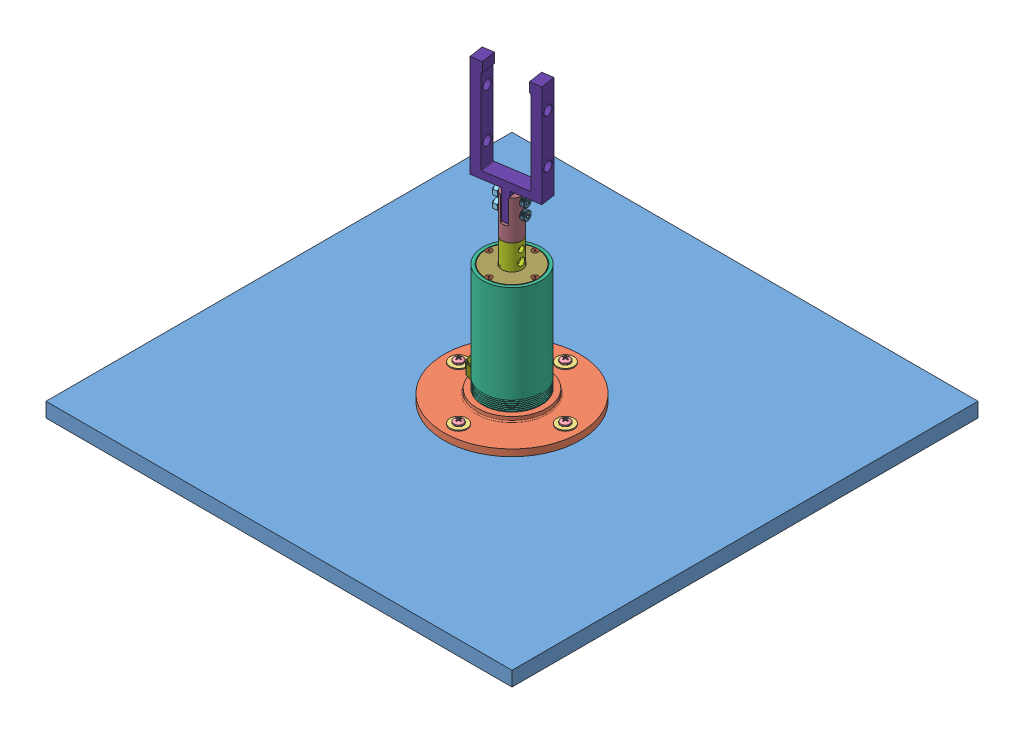
SolidWorks assembly 00_Full Planarizer Assembly, configuration Default. Lengths in mm.
Overall size (609.6 397.76 609.6).
39 component instances, 17 part files, 4 mates.
Components (placement in the parent):
- 00_01_Base_Assembly-1: 00_01_Base_Assembly [Default] at origin size (609.6 258.13 609.6)
  - 00_01_01_Base_Plate-2: 00_01_01_Base_Plate [Default] at (304.8 -19.05 304.8) x (0 0 -1) z (1 0 0) size (609.6 19.05 609.6)
  - 00_01_02_Base_Flange-1: 00_01_02_Base_Flange [Default] at origin size (177.8 15.35 177.8)
  - 00_01_03_91090A107_Zinc-Plated Steel Oversized Washer-2: 00_01_03_91090A107_Zinc-Plated Steel Oversized Washer [91090A107] at (0 10.0584 -69.85) x (0 -1 0) z (0 0 1) size (1.3 22.23 22.23)
  - 00_01_03_91090A107_Zinc-Plated Steel Oversized Washer-1: 00_01_03_91090A107_Zinc-Plated Steel Oversized Washer [91090A107] at (0 10.0584 69.85) x (0 -1 0) z (0 0 -1) size (1.3 22.23 22.23)
  - 00_01_03_91090A107_Zinc-Plated Steel Oversized Washer-3: 00_01_03_91090A107_Zinc-Plated Steel Oversized Washer [91090A107] at (69.85 10.0584 0) x (0 -1 0) z (0 0 -1) size (1.3 22.23 22.23)
  - 00_01_03_91090A107_Zinc-Plated Steel Oversized Washer-4: 00_01_03_91090A107_Zinc-Plated Steel Oversized Washer [91090A107] at (-69.85 10.0584 0) x (0 -1 0) z (0 0 -1) size (1.3 22.23 22.23)
  - 00_01_04_91772A543_Passivated 18-8 Stainless Steel Pan Head Phillips Screw-1: 00_01_04_91772A543_Passivated 18-8 Stainless Steel Pan Head Phillips Screw [91772A543] at (0 -18.5166 69.85) x (-1 0 0) z (0 1 0) size (12.5 12.5 33.12)
  - 00_01_04_91772A543_Passivated 18-8 Stainless Steel Pan Head Phillips Screw-2: 00_01_04_91772A543_Passivated 18-8 Stainless Steel Pan Head Phillips Screw [91772A543] at (-69.85 -18.5166 0) x (-1 0 0) z (0 1 0) size (12.5 12.5 33.12)
  - 00_01_04_91772A543_Passivated 18-8 Stainless Steel Pan Head Phillips Screw-3: 00_01_04_91772A543_Passivated 18-8 Stainless Steel Pan Head Phillips Screw [91772A543] at (69.85 -18.5166 0) x (-1 0 0) z (0 1 0) size (12.5 12.5 33.12)
  - 00_01_04_91772A543_Passivated 18-8 Stainless Steel Pan Head Phillips Screw-4: 00_01_04_91772A543_Passivated 18-8 Stainless Steel Pan Head Phillips Screw [91772A543] at (0 -18.5166 -69.85) x (-1 0 0) z (0 1 0) size (12.5 12.5 33.12)
  - 00_01_05_95462A029_Medium-Strength Steel Hex Nut-1: 00_01_05_95462A029_Medium-Strength Steel Hex Nut [95462A029] at (0 -15.4781 69.85) x (1 0 0) z (0 1 0) size (11.11 12.83 6.51)
  - 00_01_05_95462A029_Medium-Strength Steel Hex Nut-2: 00_01_05_95462A029_Medium-Strength Steel Hex Nut [95462A029] at (-69.85 -15.4781 0) x (1 0 0) z (0 -1 0) size (11.11 12.83 6.51)
  - 00_01_05_95462A029_Medium-Strength Steel Hex Nut-3: 00_01_05_95462A029_Medium-Strength Steel Hex Nut [95462A029] at (0 -15.4781 -69.85) x (1 0 0) z (0 1 0) size (11.11 12.83 6.51)
  - 00_01_05_95462A029_Medium-Strength Steel Hex Nut-4: 00_01_05_95462A029_Medium-Strength Steel Hex Nut [95462A029] at (69.85 -15.4781 0) x (1 0 0) z (0 1 0) size (11.11 12.83 6.51)
  - 00_01_05_95462A029_Medium-Strength Steel Hex Nut-5: 00_01_05_95462A029_Medium-Strength Steel Hex Nut [95462A029] at (-15.3027 232.664 2.3238) x (-0.150135 0 -0.988666) z (0.988666 0 -0.150135) size (11.11 12.83 6.51)
  - 00_01_05_95462A029_Medium-Strength Steel Hex Nut-6: 00_01_05_95462A029_Medium-Strength Steel Hex Nut [95462A029] at (-15.3027 217.424 2.3238) x (-0.150135 0 -0.988666) z (0.988666 0 -0.150135) size (11.11 12.83 6.51)
  - 00_01_06_Fixed_Housing-2: 00_01_06_Fixed_Housing [Default] at (0 28.575 0) x (1 0 0) z (0 -1 0) size (78.23 80.13 152.8)
  - 00_01_07_Base_Shaft-1: 00_01_07_Base_Shaft [Default] at (0 16.764 0) x (-1 0 0) z (0 1 0) size (31.75 31.75 171.45)
  - 00_01_08_AST_Bearings_R16ZZ-1: 00_01_08_AST_Bearings_R16ZZ [Default] at (0 136.525 0) x (0 1 0) z (0 0 -1) size (12.7 50.8 50.8)
  - 00_01_08_AST_Bearings_R16ZZ-2: 00_01_08_AST_Bearings_R16ZZ [Default] at (0 92.075 0) x (0 1 0) z (0 0 -1) size (12.7 50.8 50.8)
  - 00_01_09_97633A300_External Retaining Ring-1: 00_01_09_97633A300_External Retaining Ring [97633A300] at (0 147.4724 0) x (0 1 0) z (0 0 1) size (1.07 30.68 28.04)
  - 00_01_10_Encoder_Plate-2: 00_01_10_Encoder_Plate [Default] at (0 38.1 0) x (0 0 1) z (1 0 0) size (87.12 6.63 58.67)
  - 00_01_11_92210A161_18-8 Stainless Steel Hex Drive Flat Head Screw-1: 00_01_11_92210A161_18-8 Stainless Steel Hex Drive Flat Head Screw [92210A161] at (0 150.8618 -30.226) x (1 0 0) z (0 1 0) size (7.8 7.8 9.86)
  - 00_01_11_92210A161_18-8 Stainless Steel Hex Drive Flat Head Screw-2: 00_01_11_92210A161_18-8 Stainless Steel Hex Drive Flat Head Screw [92210A161] at (-30.226 150.8618 0) x (1 0 0) z (0 1 0) size (7.8 7.8 9.86)
  - 00_01_11_92210A161_18-8 Stainless Steel Hex Drive Flat Head Screw-3: 00_01_11_92210A161_18-8 Stainless Steel Hex Drive Flat Head Screw [92210A161] at (0 150.8618 30.226) x (1 0 0) z (0 1 0) size (7.8 7.8 9.86)
  - 00_01_11_92210A161_18-8 Stainless Steel Hex Drive Flat Head Screw-5: 00_01_11_92210A161_18-8 Stainless Steel Hex Drive Flat Head Screw [92210A161] at (-5.715 36.4632 9.8987) x (1 0 0) z (0 -1 0) size (7.8 7.8 9.86)
  - 00_01_11_92210A161_18-8 Stainless Steel Hex Drive Flat Head Screw-6: 00_01_11_92210A161_18-8 Stainless Steel Hex Drive Flat Head Screw [92210A161] at (0 36.4632 30.226) x (1 0 0) z (0 -1 0) size (7.8 7.8 9.86)
  - 00_01_11_92210A161_18-8 Stainless Steel Hex Drive Flat Head Screw-7: 00_01_11_92210A161_18-8 Stainless Steel Hex Drive Flat Head Screw [92210A161] at (30.226 36.4632 0) x (1 0 0) z (0 -1 0) size (7.8 7.8 9.86)
  - 00_01_11_92210A161_18-8 Stainless Steel Hex Drive Flat Head Screw-8: 00_01_11_92210A161_18-8 Stainless Steel Hex Drive Flat Head Screw [92210A161] at (0 36.4632 -30.226) x (1 0 0) z (0 -1 0) size (7.8 7.8 9.86)
  - 00_01_11_92210A161_18-8 Stainless Steel Hex Drive Flat Head Screw-4: 00_01_11_92210A161_18-8 Stainless Steel Hex Drive Flat Head Screw [92210A161] at (30.226 150.8618 0) x (1 0 0) z (0 1 0) size (7.8 7.8 9.86)
  - 00_01_12_Cover_Plate-1: 00_01_12_Cover_Plate [Default] at (0 149.225 0) size (66.55 6.63 66.55)
  - 00_01_13_Base_Adapter-1: 00_01_13_Base_Adapter [Slot_and_Screw_Top] at (0 239.014 0) x (-0.988666 0 0.150135) z (-0.150135 0 -0.988666) size (25.4 63.5 25.4)
  - 00_01_14_1220_91259A582_Alloy Steel Shoulder Screw-1: 00_01_14_1220_91259A582_Alloy Steel Shoulder Screw [91259A582] at (18.0493 232.664 -2.7409) x (-0.150135 0 -0.988666) z (0.988666 0 -0.150135) size (11.11 11.11 39.65)
  - 00_01_14_1220_91259A582_Alloy Steel Shoulder Screw-2: 00_01_14_1220_91259A582_Alloy Steel Shoulder Screw [91259A582] at (18.0493 217.424 -2.7409) x (-0.150135 0 -0.988666) z (0.988666 0 -0.150135) size (11.11 11.11 39.65)
  - 00_01_15_SlipRing-1: 00_01_15_SlipRing [Default] at (0 41.2257 0) size (54 38.66 54)
  - 00_01_16_E6-X-500-X-D-H-D-X-1: 00_01_16_E6-X-500-X-D-H-D-X [Default] at (0 31.75 0) x (0 0 -1) z (-1 0 0) size (56.39 16.59 76.2)
- 00_02_Holder_Assembly^00_Full Planarizer Assembly-1: 00_02_Holder_Assembly^00_Full Planarizer Assembly [Default] at (0 207.264 0) x (0.150135 0 0.988666) z (-0.988666 0 0.150135) size (19.05 171.45 82.55) (virtual)
  - 00_02_01_Clevis_Hand-1: 00_02_01_Clevis_Hand [Tab_In_Slot_W_Holes] x (0 0 -1) z (1 0 0) size (82.55 171.45 19.05)
Mates (geometry in assembly coordinates):
- Coincident1: coordinate: point of 00_01_Base_Assembly-1/00_01_02_Base_Flange-1
- Coincident2: coincident anti-aligned: plane of 00_02_Holder_Assembly^00_Full Planarizer Assembly-1 through (0 207.264 0) normal (0.150135 0 0.988666); plane of 00_01_Base_Assembly-1/00_01_13_Base_Adapter-1 through (0 239.014 0) normal (-0.150135 0 -0.988666)
- Coincident4: coincident aligned: plane of 00_01_Base_Assembly-1/00_01_13_Base_Adapter-1 through (0 207.264 0) normal (0 1 0); plane of 00_02_Holder_Assembly^00_Full Planarizer Assembly-1 through (0 207.264 0) normal (0 1 0)
- Coincident5: coincident aligned: plane of 00_01_Base_Assembly-1/00_01_13_Base_Adapter-1 through (0 239.014 0) normal (-0.988666 0 0.150135); plane of 00_02_Holder_Assembly^00_Full Planarizer Assembly-1 through (0 207.264 0) normal (-0.988666 0 0.150135)
